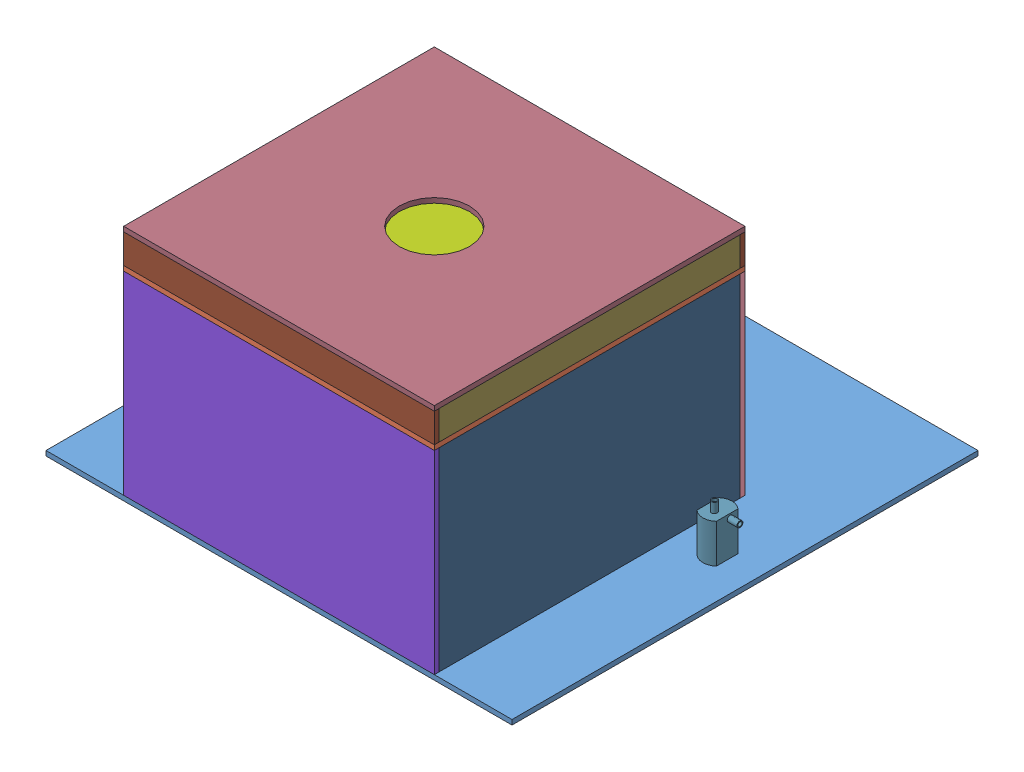
SolidWorks assembly HomeModel, configuration Default. Lengths in mm.
Overall size (609.6 311.15 609.6).
17 component instances, 14 part files, 45 mates.
Components (placement in the parent):
- BaseBoard-1: BaseBoard [Default] at (266.1639 290.2349 464.3322) size (609.6 6.35 609.6)
- Ceiling-1: Ceiling [Default] at (266.1639 550.5849 565.9322) size (406.4 6.35 406.4)
- FrontDoor-1: FrontDoor [Default] at (266.1639 298.1724 369.0822) x (-1 0 0) z (0 0 -1) size (123.83 200.03 6.35)
- FrontWall-1: FrontWall [Default] at (266.1639 296.5849 362.7322) size (406.4 254 6.35)
- FrontWindow-1: FrontWindow [Default] at (132.8139 423.5849 362.7322) size (76.2 76.2 6.35)
- FrontWindow-2: FrontWindow [Default] at (399.5139 423.5849 362.7322) size (76.2 76.2 6.35)
- DSP_Board_AJA-1: DSP_Board_AJA [Default] at (187.3534 563.1062 776.1914) x (0.995423 0 -0.095562) z (0 1 0) size (152.4 101.6 5.49)
- Fan-1: Fan [Default] at (265.8539 556.9349 565.6222) size (119.38 25.4 119.38)
- BackWall-1: BackWall [Default] at (266.1639 296.5849 762.7822) size (406.4 254 6.35)
- Senior_DoorLock-1: Senior_DoorLock [Default] at (98.5304 288.4372 369.4937) size (58.93 46.99 19.71)
- SideWall-1: SideWall [Default] at (469.3639 296.5849 565.9322) x (0 0 1) z (0 -1 0) size (393.7 6.35 254)
- RoofFrontBack-1: RoofFrontBack [Default] at (266.1639 556.9349 762.7822) size (406.4 38.1 6.35)
- RoofFrontBack-2: RoofFrontBack [Default] at (266.1639 556.9349 362.7322) size (406.4 38.1 6.35)
- RoofSide-1: RoofSide [Default] at (62.9639 556.9349 565.9322) size (6.35 38.1 393.7)
- RoofSide-2: RoofSide [Default] at (463.0139 556.9349 565.9322) size (6.35 38.1 393.7)
- RoofTop-1: RoofTop [Default] at (266.1639 595.0349 769.1322) size (406.4 6.35 406.4)
- Pump-1: Pump [Default] at (518.2076 296.5849 447.5851) x (0 0 1) z (-1 0 0) size (38.1 63.5 38.1)
Mates (geometry in assembly coordinates):
- Coincident1: coincident aligned: plane of BaseBoard-1 through (266.1639 296.5849 464.3322) normal (0 1 0); plane of FrontWall-1 through (266.1639 296.5849 362.7322) normal (0 1 0)
- Distance1: distance = 203.2 mm: line of FrontWall-1 through (62.9639 296.5849 362.7322) axis (1 0 0); line of BaseBoard-1 through (570.9639 296.5849 159.5322) axis (-1 0 0)
- Distance2: distance = 101.6 mm: line of FrontWall-1 through (62.9639 296.5849 369.0822) axis (0 0 -1); line of BaseBoard-1 through (-38.6361 296.5849 159.5322) axis (0 0 1)
- Parallel3: parallel aligned: plane of FrontDoor-1 through (266.1639 298.1724 369.0822) normal (0 0 1); plane of FrontWall-1 through (266.1639 296.5849 369.0822) normal (0 0 1)
- Parallel4: parallel aligned: line of FrontDoor-1 through (204.2514 498.1974 362.7322) axis (1 0 0); line of FrontWall-1 through (202.6639 499.7849 362.7322) axis (1 0 0)
- Distance3: distance = 1.5875 mm anti-aligned: plane of FrontDoor-1 through (328.0764 498.1974 362.7322) normal (1 0 0); plane of FrontWall-1 through (329.6639 499.7849 362.7312) normal (-1 0 0)
- Distance4: distance = 1.5875 mm anti-aligned: plane of FrontDoor-1 through (328.0764 498.1974 362.7322) normal (0 1 0); plane of FrontWall-1 through (202.6639 499.7849 362.7312) normal (0 -1 0)
- Coincident8: coincident aligned: plane of FrontDoor-1 through (266.1639 298.1724 362.7322) normal (0 0 -1); plane of FrontWall-1 through (266.1639 296.5849 362.7322) normal (0 0 -1)
- Coincident9: coincident aligned: plane of FrontWall-1 through (266.1639 296.5849 362.7322) normal (0 0 -1); plane of FrontWindow-2 through (399.5139 423.5849 362.7322) normal (0 0 -1)
- Coincident10: coincident anti-aligned: line of FrontWall-1 through (361.4139 461.6849 362.7322) axis (1 0 0); line of FrontWindow-2 through (437.6139 461.6849 362.7322) axis (-1 0 0)
- Coincident11: coincident anti-aligned: line of FrontWall-1 through (437.6139 461.6849 362.7322) axis (0 -1 0); line of FrontWindow-2 through (437.6139 385.4849 362.7322) axis (0 1 0)
- Coincident12: coincident anti-aligned: line of FrontWall-1 through (170.9139 461.6849 362.7322) axis (0 -1 0); line of FrontWindow-1 through (170.9139 385.4849 362.7322) axis (0 1 0)
- Coincident13: coincident anti-aligned: line of FrontWall-1 through (94.7139 461.6849 362.7322) axis (1 0 0); line of FrontWindow-1 through (170.9139 461.6849 362.7322) axis (-1 0 0)
- Coincident14: coincident aligned: plane of FrontWall-1 through (266.1639 296.5849 362.7322) normal (0 0 -1); plane of FrontWindow-1 through (132.8139 423.5849 362.7322) normal (0 0 -1)
- Coincident15: coincident anti-aligned: plane of Ceiling-1 through (266.1639 550.5849 565.9322) normal (0 -1 0); plane of FrontWall-1 through (62.9639 550.5849 369.0822) normal (0 1 0)
- Coincident16: coincident: plane of Ceiling-1 through (469.3639 556.9349 362.7322) normal (1 0 0); line of FrontWall-1 through (469.3639 550.5849 369.0822) axis (0 0 -1)
- Coincident17: coincident aligned: line of Ceiling-1 through (469.3639 550.5849 362.7322) axis (-1 0 0); line of FrontWall-1 through (469.3639 550.5849 362.7322) axis (-1 0 0)
- Concentric4: concentric aligned: cylinder of Ceiling-1 through (213.6639 550.5839 513.4322) axis (0 1 0) radius 2.165; cylinder of Fan-1 through (213.6639 556.9339 513.4322) axis (0 1 0) radius 2.165
- Coincident18: coincident anti-aligned: plane of Ceiling-1 through (266.1639 556.9349 565.9322) normal (0 1 0); plane of Fan-1 through (265.8539 556.9349 565.6222) normal (0 -1 0)
- Parallel9: parallel anti-aligned: plane of Ceiling-1 through (266.1639 556.9349 565.9322) normal (0 1 0); plane of DSP_Board_AJA-1 through (210.2098 562.6948 748.4804) normal (0 -1 0)
- Parallel10: parallel aligned: plane of FrontWall-1 through (266.1639 296.5849 369.0822) normal (0 0 1); plane of BackWall-1 through (266.1639 296.5849 769.1322) normal (0 0 1)
- Coincident22: coincident: moEndPointRef_w of BaseBoard-1; moEndPointRef_w of BackWall-1
- Parallel11: parallel anti-aligned: line of Ceiling-1 through (62.9639 550.5849 769.1322) axis (1 0 0); line of BackWall-1 through (469.3639 550.5849 769.1322) axis (-1 0 0)
- Coincident24: coincident anti-aligned: line of FrontWall-1 through (469.3639 296.5849 369.0822) axis (0 1 0); line of SideWall-1 through (469.3639 550.5849 369.0822) axis (0 -1 0)
- Coincident27: coincident anti-aligned: plane of BaseBoard-1 through (266.1639 296.5849 464.3322) normal (0 1 0); plane of SideWall-1 through (463.0139 296.5849 369.0822) normal (0 -1 0)
- Parallel13: parallel anti-aligned: plane of BackWall-1 through (266.1639 296.5849 762.7822) normal (0 0 -1); plane of SideWall-1 through (463.0139 550.5849 762.7822) normal (0 0 1)
- Coincident28: coincident anti-aligned: plane of Ceiling-1 through (266.1639 556.9349 565.9322) normal (0 1 0); plane of RoofFrontBack-1 through (62.9639 556.9349 769.1322) normal (0 -1 0)
- Coincident29: coincident aligned: line of Ceiling-1 through (62.9639 556.9349 769.1322) axis (1 0 0); line of RoofFrontBack-1 through (62.9639 556.9349 769.1322) axis (1 0 0)
- Coincident30: coincident aligned: plane of Ceiling-1 through (469.3639 556.9349 362.7322) normal (1 0 0); plane of RoofFrontBack-1 through (469.3639 595.0349 769.1322) normal (1 0 0)
- Coincident31: coincident anti-aligned: plane of Ceiling-1 through (266.1639 556.9349 565.9322) normal (0 1 0); plane of RoofFrontBack-2 through (62.9639 556.9349 369.0822) normal (0 -1 0)
- Coincident32: coincident aligned: plane of Ceiling-1 through (469.3639 556.9349 362.7322) normal (1 0 0); plane of RoofFrontBack-2 through (469.3639 595.0349 369.0822) normal (1 0 0)
- Coincident33: coincident anti-aligned: line of Ceiling-1 through (469.3639 556.9349 362.7322) axis (-1 0 0); line of RoofFrontBack-2 through (62.9639 556.9349 362.7322) axis (1 0 0)
- Coincident34: coincident anti-aligned: plane of RoofFrontBack-2 through (266.1639 556.9349 369.0822) normal (0 0 1); plane of RoofSide-1 through (69.3139 595.0349 369.0822) normal (0 0 -1)
- Coincident35: coincident anti-aligned: plane of Ceiling-1 through (266.1639 556.9349 565.9322) normal (0 1 0); plane of RoofSide-1 through (69.3139 556.9349 762.7822) normal (0 -1 0)
- Coincident36: coincident anti-aligned: line of Ceiling-1 through (62.9639 556.9349 362.7322) axis (0 0 1); line of RoofSide-1 through (62.9639 556.9349 762.7822) axis (0 0 -1)
- Coincident37: coincident anti-aligned: plane of Ceiling-1 through (266.1639 556.9349 565.9322) normal (0 1 0); plane of RoofSide-2 through (469.3639 556.9349 762.7822) normal (0 -1 0)
- Coincident38: coincident anti-aligned: plane of RoofFrontBack-1 through (266.1639 556.9349 762.7822) normal (0 0 -1); plane of RoofSide-2 through (469.3639 595.0349 762.7822) normal (0 0 1)
- Coincident39: coincident aligned: line of Ceiling-1 through (469.3639 556.9349 769.1322) axis (0 0 -1); line of RoofSide-2 through (469.3639 556.9349 762.7822) axis (0 0 -1)
- Coincident40: coincident anti-aligned: plane of RoofFrontBack-2 through (62.9639 595.0349 369.0822) normal (0 1 0); plane of RoofTop-1 through (266.1639 595.0349 769.1322) normal (0 -1 0)
- Coincident41: coincident aligned: line of RoofFrontBack-2 through (469.3639 595.0349 362.7322) axis (-1 0 0); line of RoofTop-1 through (469.3639 595.0349 362.7322) axis (-1 0 0)
- Coincident42: coincident aligned: line of RoofSide-1 through (62.9639 595.0349 369.0822) axis (0 0 1); line of RoofTop-1 through (62.9639 595.0349 362.7322) axis (0 0 1)
- Coincident43: coincident anti-aligned: plane of FrontWall-1 through (266.1639 296.5849 369.0822) normal (0 0 1); plane of Senior_DoorLock-1 through (123.9304 313.8372 369.0822) normal (0 0 -1)
- Parallel14: parallel: plane of FrontWall-1 through (266.1639 296.5849 369.0822) normal (0 0 1); line of Senior_DoorLock-1 through (123.9304 360.1922 369.4937) axis (0 -1 0)
- Parallel15: parallel: plane of FrontWall-1 through (266.1639 296.5849 369.0822) normal (0 0 1); line of Senior_DoorLock-1 through (123.9304 313.8372 369.4937) axis (1 0 0)
- Coincident47: coincident anti-aligned: plane of BaseBoard-1 through (266.1639 296.5849 464.3322) normal (0 1 0); plane of Pump-1 through (518.2076 296.5849 447.5851) normal (0 -1 0)
